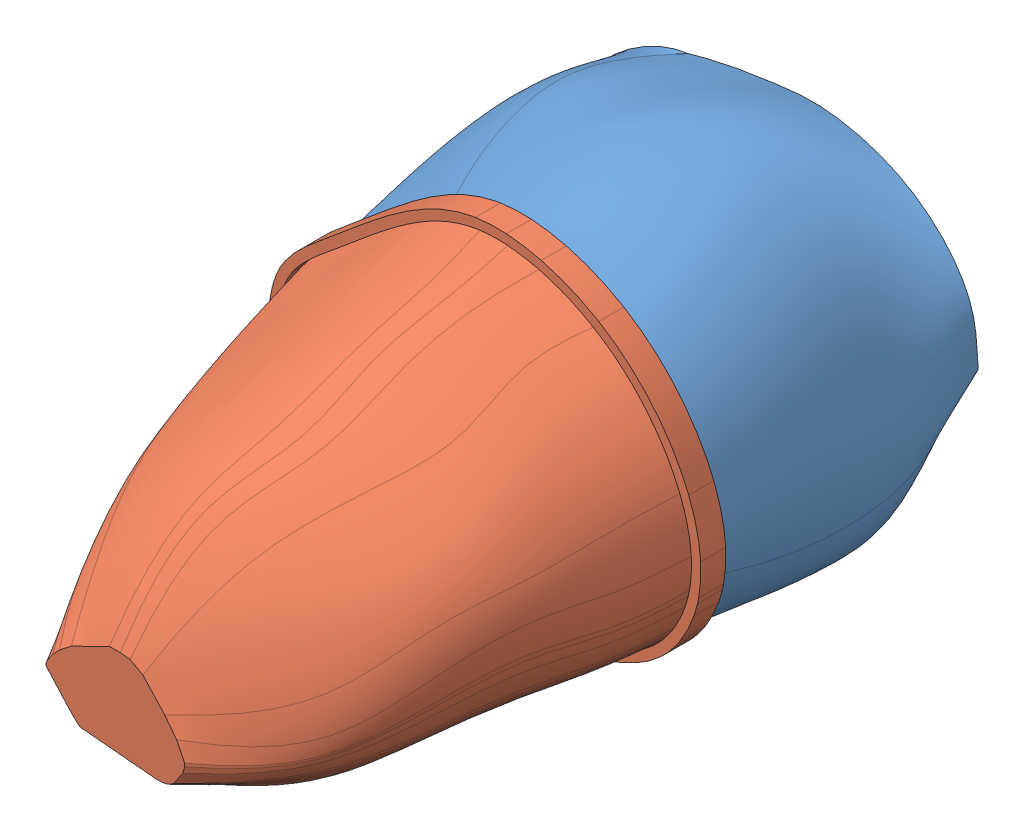
SolidWorks assembly L-LunRL, configuration Default. Lengths in mm.
Overall size (148.5 124.29 197.31).
2 component instances, 2 part files, 0 mates.
Components (placement in the parent):
- L-LunRL_lower-1: L-LunRL_lower [Default] at (13.945 143.7795 63.1542) size (146.85 124.29 85.91)
- L-lunRL_upper-1: L-lunRL_upper [Default] at (14.8995 145.0113 68.2723) size (145.16 118.56 123.27)
